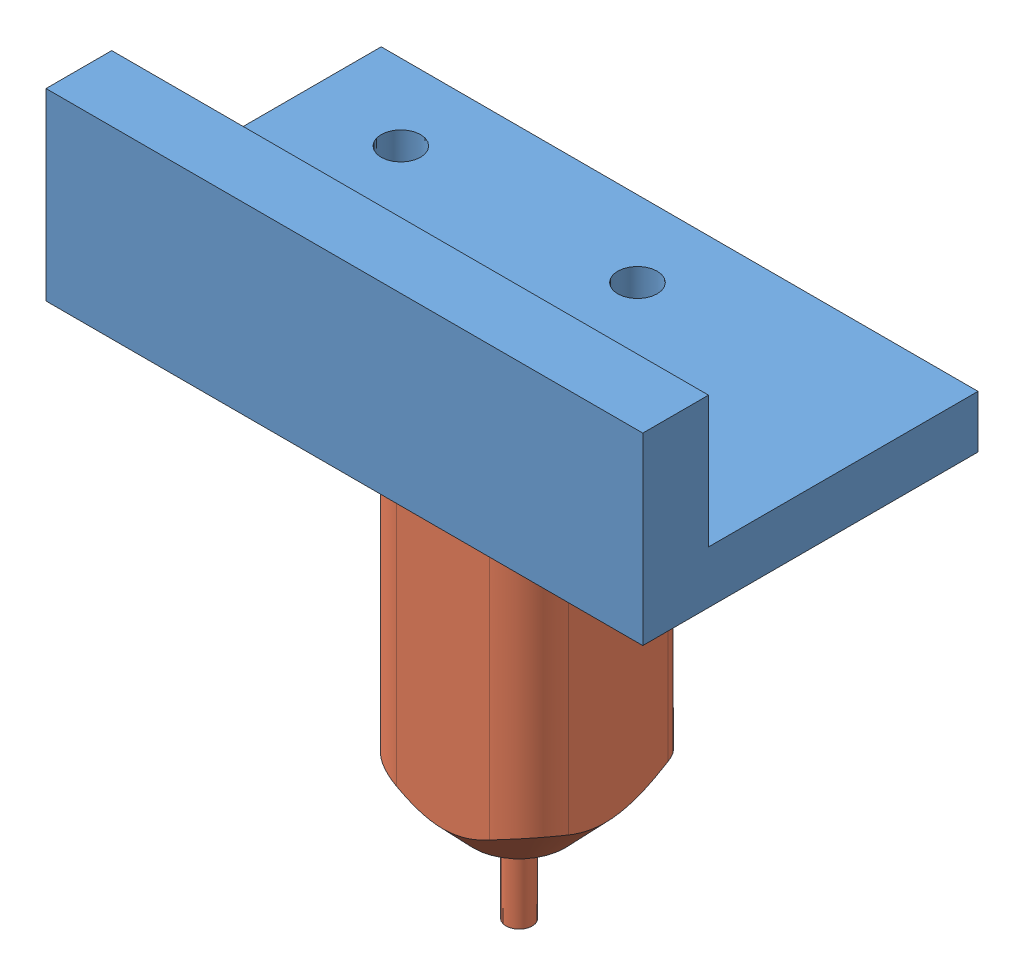
SolidWorks assembly BL Touch Mount, configuration Default. Lengths in mm.
Overall size (45.4 56.15 32.72).
2 component instances, 2 part files, 3 mates.
Components (placement in the parent):
- BL Touch Mount v2-1: BL Touch Mount v2 [Default] at (27.8645 153.9222 269.633) x (1 0 0) z (0 0 -1) size (45.4 13.75 25.5)
- BL-touch-1: BL-touch [Predeterminado] at (44.1413 149.9222 275.4167) x (-1 0 0) z (0 1 0) size (26 26 42.4)
Mates (geometry in assembly coordinates):
- Coincident403: coincident anti-aligned: plane of BL-touch-1 through (53.1415 149.9222 275.4157) normal (0 1 0); plane of BL Touch Mount v2-1 through (27.8645 149.9222 269.633) normal (0 -1 0)
- Distance1: distance = 9.75 mm aligned: plane of BL Touch Mount v2-1 through (27.8645 149.9222 269.633) normal (-1 0 0); plane of BL-touch-1 through (37.6145 113.9222 278.2005) normal (-1 0 0)
- Coincident408: coincident aligned: plane of BL Touch Mount v2-1 through (27.8645 149.9222 269.633) normal (0 0 -1); plane of BL-touch-1 through (49.6682 113.9222 269.633) normal (0 0 -1)
